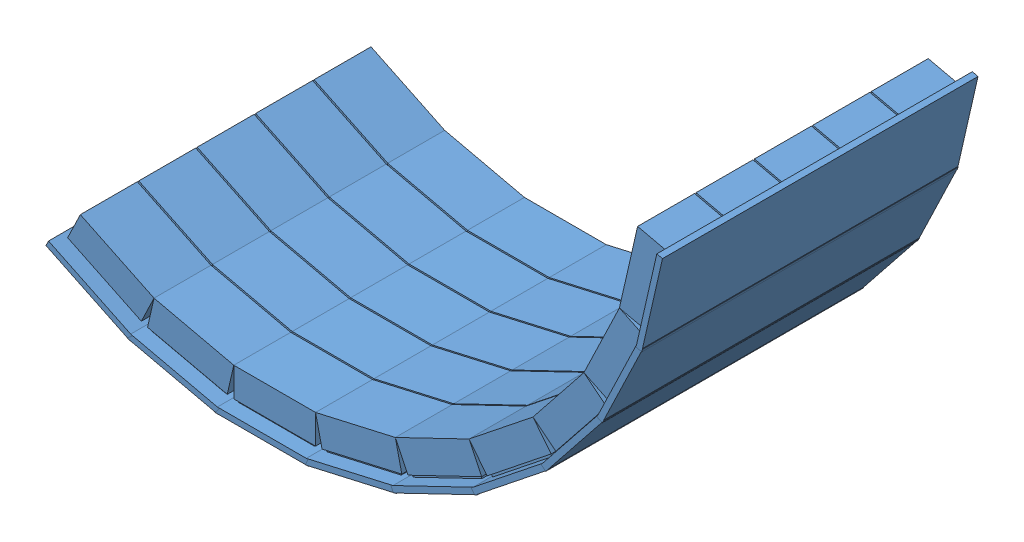
SolidWorks assembly CshapedDetector1, configuration Default. Lengths in mm.
Overall size (527.59 312.86 270).
9 component instances, 1 part files, 26 mates.
Components (placement in the parent):
- 5Detector-1: 5Detector [Default] at (91.8512 126.8436 184.2598) size (80 32 270)
- 5Detector-2: 5Detector [Default] at (168.0955 135.4362 184.2598) x (0.974917 0.22257 0) z (0 0 1) size (80 32 270)
- 5Detector-4: 5Detector [Default] at (240.515 160.783 184.2598) x (0.900926 0.433974 0) z (0 0 1) size (80 32 270)
- 5Detector-5: 5Detector [Default] at (305.4764 201.6123 184.2598) x (0.781738 0.623607 0) z (0 0 1) size (80 32 270)
- 5Detector-6: 5Detector [Default] at (359.7211 255.8759 184.2598) x (0.623334 0.781956 0) z (0 0 1) size (80 32 270)
- 5Detector-7: 5Detector [Default] at (400.5278 320.8517 184.2598) x (0.433659 0.901077 0) z (0 0 1) size (80 32 270)
- 5Detector-8: 5Detector [Default] at (15.6069 135.4362 184.2598) x (0.974917 -0.22257 0) z (0 0 1) size (80 32 270)
- 5Detector-9: 5Detector [Default] at (-56.8125 160.783 184.2598) x (0.900926 -0.433974 0) z (0 0 1) size (80 32 270)
- 5Detector-10: 5Detector [Default] at (425.8492 393.2799 184.2598) x (0.222229 0.974994 0) z (0 0 1) size (80 32 270)
Mates (geometry in assembly coordinates):
- Coincident2: coincident anti-aligned: line of 5Detector-1 through (126.8512 158.8436 308.2693) axis (0 0 -1); line of 5Detector-2 through (126.8512 158.8436 259.5203) axis (0 0 1)
- Parallel1: parallel anti-aligned: line of 5Detector-1 through (126.8512 158.8436 308.2693) axis (0 0 -1); line of 5Detector-2 through (126.8512 158.8436 259.5203) axis (0 0 1)
- Angle6: planar angle = 2.917143 rad anti-aligned: line of 5Detector-2 through (126.8512 158.8436 308.2693) axis (0.974917 0.22257 0); line of 5Detector-1 through (56.8512 158.8436 308.2693) axis (1 0 0)
- Coincident12: coincident: line of 5Detector-1 through (126.8512 158.8436 308.2693) axis (0 0 -1); plane of 5Detector-2 through (160.9733 166.6336 184.2598) normal (-0.22257 0.974917 0)
- Coincident19: coincident anti-aligned: line of 5Detector-2 through (195.0954 174.4235 308.2693) axis (0 0 -1); line of 5Detector-4 through (195.0954 174.4235 259.5203) axis (0 0 1)
- Coincident22: coincident: point of 5Detector-1; point of 5Detector-2
- Angle9: planar angle = 2.917143 rad anti-aligned: line of 5Detector-4 through (195.0954 174.4235 308.2693) axis (0.900926 0.433974 0); line of 5Detector-2 through (126.8512 158.8436 308.2693) axis (0.974917 0.22257 0)
- Coincident24: coincident: point of 5Detector-2; point of 5Detector-4
- Coincident25: coincident anti-aligned: line of 5Detector-4 through (258.1602 204.8017 308.2693) axis (0 0 -1); line of 5Detector-5 through (258.1602 204.8017 259.5203) axis (0 0 1)
- Angle10: planar angle = 2.917143 rad anti-aligned: line of 5Detector-5 through (258.1602 204.8017 308.2693) axis (0.781738 0.623607 0); line of 5Detector-4 through (195.0954 174.4235 308.2693) axis (0.900926 0.433974 0)
- Coincident27: coincident: point of 5Detector-4; point of 5Detector-5
- Coincident28: coincident anti-aligned: line of 5Detector-5 through (312.8819 248.4541 308.2693) axis (0 0 -1); line of 5Detector-6 through (312.8819 248.4541 259.5203) axis (0 0 1)
- Angle11: planar angle = 2.917143 rad anti-aligned: line of 5Detector-6 through (312.8819 248.4541 308.2693) axis (0.623334 0.781956 0); line of 5Detector-5 through (258.1602 204.8017 308.2693) axis (0.781738 0.623607 0)
- Coincident30: coincident: point of 5Detector-5; point of 5Detector-6
- Coincident31: coincident: line of 5Detector-6 through (356.5152 303.191 308.2693) axis (0 0 -1); line of 5Detector-7 through (356.5152 303.191 259.5203) axis (0 0 1)
- Angle12: planar angle = 2.917143 rad: line of 5Detector-6 through (312.8819 248.4541 308.2693) axis (0.623334 0.781956 0); line of 5Detector-7 through (356.5152 303.191 308.2693) axis (0.433659 0.901077 0)
- Coincident33: coincident: point of 5Detector-6; point of 5Detector-7
- Coincident34: coincident: line of 5Detector-1 through (56.8512 158.8436 259.5203) axis (0 0 1); line of 5Detector-8 through (56.8512 158.8436 308.2693) axis (0 0 -1)
- Angle13: planar angle = 2.917143 rad: line of 5Detector-1 through (56.8512 158.8436 308.2693) axis (1 0 0); line of 5Detector-8 through (-11.393 174.4235 308.2693) axis (0.974917 -0.22257 0)
- Coincident36: coincident: point of 5Detector-1; point of 5Detector-8
- Coincident37: coincident: line of 5Detector-8 through (-11.393 174.4235 259.5203) axis (0 0 1); line of 5Detector-9 through (-11.393 174.4235 308.2693) axis (0 0 -1)
- Angle14: planar angle = 2.917143 rad: line of 5Detector-9 through (-74.4577 204.8017 308.2693) axis (0.900926 -0.433974 0); line of 5Detector-8 through (-11.393 174.4235 308.2693) axis (0.974917 -0.22257 0)
- Coincident39: coincident: point of 5Detector-8; point of 5Detector-9
- Coincident40: coincident: line of 5Detector-7 through (386.8714 366.2664 308.2693) axis (0 0 -1); line of 5Detector-10 through (386.8714 366.2664 259.5203) axis (0 0 1)
- Angle15: planar angle = 2.917143 rad: line of 5Detector-10 through (386.8714 366.2664 308.2693) axis (0.222229 0.974994 0); line of 5Detector-7 through (356.5152 303.191 308.2693) axis (0.433659 0.901077 0)
- Coincident42: coincident: point of 5Detector-7; point of 5Detector-10
